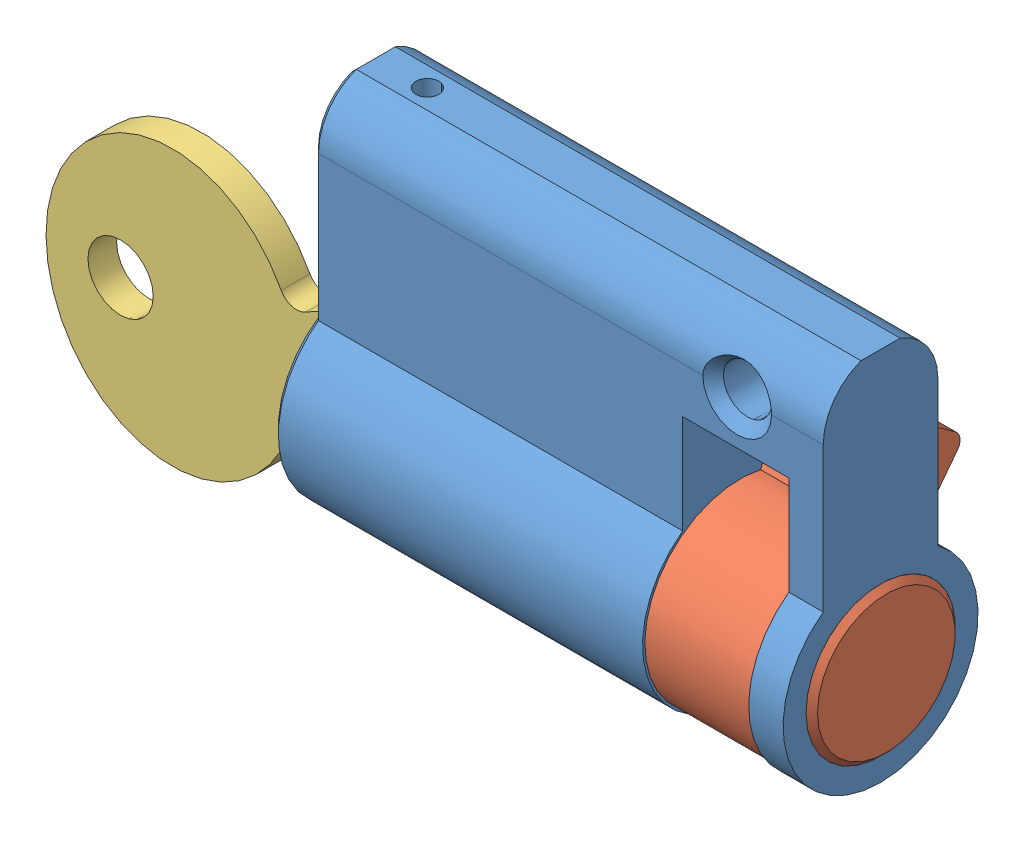
SolidWorks assembly lock_assy_5_parts_flat, configuration Default. Lengths in mm.
Overall size (72 38.45 18.44).
5 component instances, 5 part files, 9 mates.
Components (placement in the parent):
- cylinder_d-1: cylinder_d [one-pair_of_pins] at origin size (44.5 32.7 17)
- core_c-1: core_c [one-pair_of_pins] at origin size (45.24 22.49 18.24)
- key_f-1: key_f [Default] at (0 -2.25 0) x (1 0 0) z (0 -1 0) size (59.59 2.5 24)
- lower_half_pin_x-depth_2-1: lower_half_pin_x-depth_2 [Default] at (5 7.25 0) x (0.340967 0 -0.940075) z (0.940075 0 0.340967) size (2 6.1 2)
- upper_half_pin_y-1: upper_half_pin_y [cut_depth_2] at (5 15.25 0) x (-0.028319 0 -0.999599) z (0 -1 0) size (2 2 8)
Mates (geometry in assembly coordinates):
- Concentric1: concentric aligned: cylinder of cylinder_d-1 through (37 0 0) axis (-1 0 0) radius 7.25; cylinder of core_c-1 through (32.25 0 0) axis (-1 0 0) radius 7.25
- Coincident1: coincident aligned: plane of cylinder_d-1 through (0 0 0) normal (-1 0 0); plane of core_c-1 through (0 0 0) normal (-1 0 0)
- Concentric2: concentric anti-aligned: cylinder of cylinder_d-1 through (5 35 0) axis (0 -1 0) radius 1; cylinder of lower_half_pin_x-depth_2-1 through (5 1.15 0) axis (0 1 0) radius 1
- Concentric3: concentric anti-aligned: cylinder of cylinder_d-1 through (5 35 0) axis (0 -1 0) radius 1; cylinder of upper_half_pin_y-1 through (5 7.25 0) axis (0 1 0) radius 1
- Tangent1: tangent anti-aligned: sphere of lower_half_pin_x-depth_2-1; plane of upper_half_pin_y-1 through (5 7.25 0) normal (0 -1 0)
- Coincident3: coincident anti-aligned: plane of core_c-1 through (32.25 2 -1.25) normal (0 0 1); plane of key_f-1 through (-16 -2.25 -1.25) normal (0 0 -1)
- Coincident4: coincident anti-aligned: plane of core_c-1 through (0 0 0) normal (-1 0 0); plane of key_f-1 through (0 2 1.25) normal (1 0 0)
- Coincident5: coincident anti-aligned: plane of core_c-1 through (32.25 -6.25 -1.25) normal (0 1 0); plane of key_f-1 through (0 -6.25 1.25) normal (0 -1 0)
- Coincident6: coincident anti-aligned: plane of key_f-1 through (4.5 1.15 1.25) normal (0 1 0); plane of lower_half_pin_x-depth_2-1 through (5 1.15 0) normal (0 -1 0)
